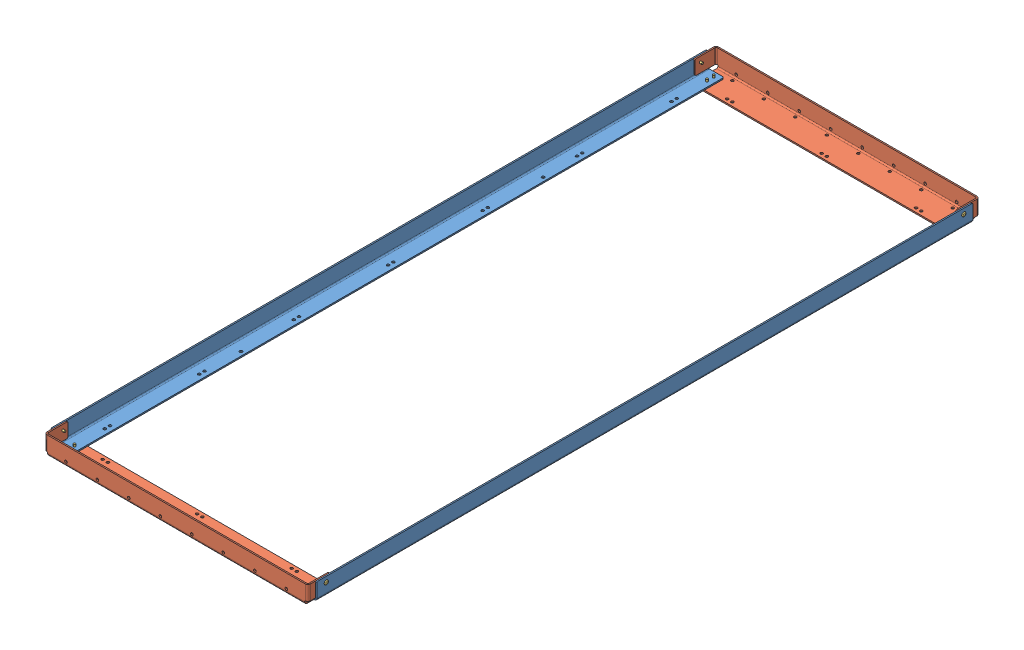
SolidWorks assembly GE-25116, configuration Default. Lengths in mm.
Overall size (647.09 46.05 1625.6).
16 component instances, 3 part files, 33 mates.
Components (placement in the parent):
- GE-25117-1: GE-25117 [Default] at (364.2844 879.7037 1220.4184) size (41.27 41.27 1587.5)
- GE-25117-2: GE-25117 [Default] at (925.6244 879.7037 1220.4184) x (-1 0 0) z (0 0 -1) size (41.27 41.27 1587.5)
- GE-25118-1: GE-25118 [Default] at (644.9544 879.7037 474.2934) size (637.54 44.45 66.67)
- GE-25118-2: GE-25118 [Default] at (644.9544 879.7037 1966.5434) x (-1 0 0) z (0 0 -1) size (637.54 44.45 66.67)
- rivet_.1875_.126-.25-1: rivet_.1875_.126-.25 [Default] at (351.5844 876.5287 2002.1034) x (1 0 0) z (0 -1 0) size (10.01 10.01 13.03)
- rivet_.1875_.126-.25-3: rivet_.1875_.126-.25 [Default] at (351.5844 876.5287 1985.5934) x (0.982082 0 -0.188455) z (0 -1 0) size (10.01 10.01 13.03)
- rivet_.1875_.126-.25-5: rivet_.1875_.126-.25 [Default] at (938.3244 876.5287 2002.1034) x (0.918365 0 -0.395734) z (0 -1 0) size (10.01 10.01 13.03)
- rivet_.1875_.126-.25-7: rivet_.1875_.126-.25 [Default] at (938.3244 876.5287 1985.5934) x (0.8 0 -0.6) z (0 -1 0) size (10.01 10.01 13.03)
- rivet_.1875_.126-.25-9: rivet_.1875_.126-.25 [Default] at (966.8994 908.2787 1991.9434) x (0 0.917795 -0.397056) z (1 0 0) size (10.01 10.01 13.03)
- rivet_.1875_.126-.25-11: rivet_.1875_.126-.25 [Default] at (323.0094 908.2787 1991.9434) x (0 0.089543 -0.995983) z (-1 0 0) size (10.01 10.01 13.03)
- rivet_.1875_.126-.25-13: rivet_.1875_.126-.25 [Default] at (351.5844 876.5287 455.2434) x (0.263225 0 -0.964735) z (0 -1 0) size (10.01 10.01 13.03)
- rivet_.1875_.126-.25-15: rivet_.1875_.126-.25 [Default] at (351.5844 876.5287 438.7334) x (0.120178 0 -0.992752) z (0 -1 0) size (10.01 10.01 13.03)
- rivet_.1875_.126-.25-17: rivet_.1875_.126-.25 [Default] at (323.0094 908.2787 448.8934) x (0 0.141223 -0.989978) z (-1 0 0) size (10.01 10.01 13.03)
- rivet_.1875_.126-.25-19: rivet_.1875_.126-.25 [Default] at (938.3244 876.5287 455.2434) x (0 0 -1) z (0 -1 0) size (10.01 10.01 13.03)
- rivet_.1875_.126-.25-21: rivet_.1875_.126-.25 [Default] at (938.3244 876.5287 438.7334) x (0.030377 0 -0.999538) z (0 -1 0) size (10.01 10.01 13.03)
- rivet_.1875_.126-.25-23: rivet_.1875_.126-.25 [Default] at (966.8994 908.2787 448.8934) x (0 -0.208456 -0.978032) z (1 0 0) size (10.01 10.01 13.03)
Mates (geometry in assembly coordinates):
- Coincident1: coincident anti-aligned: plane of fence_shortrail-1 through (326.1844 879.7037 474.2934) normal (-1 0 0); plane of fence_longrail-1 through (326.1844 879.7037 2014.1684) normal (1 0 0)
- Coincident4: coincident anti-aligned: plane of fence_shortrail-1 through (963.7244 879.7037 474.2934) normal (1 0 0); plane of fence_longrail-2 through (963.7244 879.7037 426.6684) normal (-1 0 0)
- Coincident5: coincident anti-aligned: plane of fence_shortrail-2 through (326.1844 879.7037 1966.5434) normal (-1 0 0); plane of fence_longrail-1 through (326.1844 879.7037 2014.1684) normal (1 0 0)
- Coincident6: coincident anti-aligned: plane of fence_longrail-2 through (925.6244 879.7037 426.6684) normal (0 -1 0); plane of fence_shortrail-1 through (956.1044 879.7037 474.2934) normal (0 1 0)
- Coincident8: coincident anti-aligned: plane of fence_longrail-1 through (364.2844 879.7037 2014.1684) normal (0 -1 0); plane of fence_shortrail-2 through (333.8044 879.7037 1966.5434) normal (0 1 0)
- Coincident12: coincident aligned: plane of fence_longrail-1 through (323.0094 920.9787 2014.1684) normal (0 1 0); plane of fence_shortrail-1 through (326.1844 920.9787 461.5934) normal (0 1 0)
- Concentric1: concentric anti-aligned: cylinder of fence_longrail-1 through (326.1844 908.2787 1991.9434) axis (1 0 0) radius 2.4574; cylinder of fence_shortrail-2 through (326.1844 908.2787 1991.9434) axis (-1 0 0) radius 2.4574
- Concentric2: concentric aligned: cylinder of fence_longrail-2 through (963.7244 908.2787 1991.9434) axis (-1 0 0) radius 2.4574; cylinder of fence_shortrail-2 through (326.1844 908.2787 1991.9434) axis (-1 0 0) radius 2.4574
- Concentric3: concentric anti-aligned: cylinder of fence_longrail-2 through (963.7244 908.2787 448.8934) axis (-1 0 0) radius 2.4574; cylinder of fence_shortrail-1 through (963.7244 908.2787 448.8934) axis (1 0 0) radius 2.4574
- Concentric4: concentric anti-aligned: cylinder of GE-25118-2 through (351.5844 879.7037 2002.1034) axis (0 1 0) radius 2.4574; cylinder of rivet_.1875_.126-.25-1 through (351.5844 887.9587 2002.1034) axis (0 -1 0) radius 2.3813
- Coincident13: coincident anti-aligned: plane of GE-25118-2 through (333.8044 876.5287 1966.5434) normal (0 -1 0); plane of rivet_.1875_.126-.25-1 through (351.5844 876.5287 2002.1034) normal (0 1 0)
- Concentric7: concentric anti-aligned: cylinder of GE-25118-2 through (351.5844 879.7037 1985.5934) axis (0 1 0) radius 2.4574; cylinder of rivet_.1875_.126-.25-3 through (351.5844 887.9587 1985.5934) axis (0 -1 0) radius 2.3813
- Coincident14: coincident anti-aligned: plane of GE-25118-2 through (333.8044 876.5287 1966.5434) normal (0 -1 0); plane of rivet_.1875_.126-.25-3 through (351.5844 876.5287 1985.5934) normal (0 1 0)
- Concentric8: concentric anti-aligned: cylinder of GE-25118-2 through (938.3244 879.7037 2002.1034) axis (0 1 0) radius 2.4574; cylinder of rivet_.1875_.126-.25-5 through (938.3244 887.9587 2002.1034) axis (0 -1 0) radius 2.3813
- Coincident15: coincident anti-aligned: plane of GE-25118-2 through (333.8044 876.5287 1966.5434) normal (0 -1 0); plane of rivet_.1875_.126-.25-5 through (938.3244 876.5287 2002.1034) normal (0 1 0)
- Concentric9: concentric anti-aligned: cylinder of GE-25118-2 through (938.3244 879.7037 1985.5934) axis (0 1 0) radius 2.4574; cylinder of rivet_.1875_.126-.25-7 through (938.3244 887.9587 1985.5934) axis (0 -1 0) radius 2.3813
- Coincident16: coincident anti-aligned: plane of GE-25118-2 through (333.8044 876.5287 1966.5434) normal (0 -1 0); plane of rivet_.1875_.126-.25-7 through (938.3244 876.5287 1985.5934) normal (0 1 0)
- Concentric10: concentric anti-aligned: cylinder of GE-25117-2 through (963.7244 908.2787 1991.9434) axis (-1 0 0) radius 2.4574; cylinder of rivet_.1875_.126-.25-9 through (955.4694 908.2787 1991.9434) axis (1 0 0) radius 2.3813
- Coincident17: coincident anti-aligned: plane of GE-25117-2 through (966.8994 879.7037 426.6684) normal (1 0 0); plane of rivet_.1875_.126-.25-9 through (966.8994 908.2787 1991.9434) normal (-1 0 0)
- Concentric11: concentric anti-aligned: cylinder of GE-25117-1 through (326.1844 908.2787 1991.9434) axis (1 0 0) radius 2.4574; cylinder of rivet_.1875_.126-.25-11 through (334.4394 908.2787 1991.9434) axis (-1 0 0) radius 2.3813
- Coincident18: coincident anti-aligned: plane of GE-25117-1 through (323.0094 879.7037 2014.1684) normal (-1 0 0); plane of rivet_.1875_.126-.25-11 through (323.0094 908.2787 1991.9434) normal (1 0 0)
- Concentric12: concentric anti-aligned: cylinder of GE-25118-1 through (351.5844 879.7037 455.2434) axis (0 1 0) radius 2.4574; cylinder of rivet_.1875_.126-.25-13 through (351.5844 887.9587 455.2434) axis (0 -1 0) radius 2.3813
- Coincident19: coincident anti-aligned: plane of GE-25118-1 through (956.1044 876.5287 474.2934) normal (0 -1 0); plane of rivet_.1875_.126-.25-13 through (351.5844 876.5287 455.2434) normal (0 1 0)
- Concentric13: concentric anti-aligned: cylinder of GE-25118-1 through (351.5844 879.7037 438.7334) axis (0 1 0) radius 2.4574; cylinder of rivet_.1875_.126-.25-15 through (351.5844 887.9587 438.7334) axis (0 -1 0) radius 2.3813
- Coincident20: coincident anti-aligned: plane of GE-25118-1 through (956.1044 876.5287 474.2934) normal (0 -1 0); plane of rivet_.1875_.126-.25-15 through (351.5844 876.5287 438.7334) normal (0 1 0)
- Concentric14: concentric anti-aligned: cylinder of GE-25117-1 through (326.1844 908.2787 448.8934) axis (1 0 0) radius 2.4574; cylinder of rivet_.1875_.126-.25-17 through (334.4394 908.2787 448.8934) axis (-1 0 0) radius 2.3813
- Coincident21: coincident anti-aligned: plane of GE-25117-1 through (323.0094 879.7037 2014.1684) normal (-1 0 0); plane of rivet_.1875_.126-.25-17 through (323.0094 908.2787 448.8934) normal (1 0 0)
- Concentric15: concentric anti-aligned: cylinder of GE-25118-1 through (938.3244 879.7037 455.2434) axis (0 1 0) radius 2.4574; cylinder of rivet_.1875_.126-.25-19 through (938.3244 887.9587 455.2434) axis (0 -1 0) radius 2.3813
- Coincident22: coincident anti-aligned: plane of GE-25118-1 through (956.1044 876.5287 474.2934) normal (0 -1 0); plane of rivet_.1875_.126-.25-19 through (938.3244 876.5287 455.2434) normal (0 1 0)
- Concentric16: concentric anti-aligned: cylinder of GE-25118-1 through (938.3244 879.7037 438.7334) axis (0 1 0) radius 2.4574; cylinder of rivet_.1875_.126-.25-21 through (938.3244 887.9587 438.7334) axis (0 -1 0) radius 2.3813
- Coincident23: coincident anti-aligned: plane of GE-25118-1 through (956.1044 876.5287 474.2934) normal (0 -1 0); plane of rivet_.1875_.126-.25-21 through (938.3244 876.5287 438.7334) normal (0 1 0)
- Concentric17: concentric anti-aligned: cylinder of GE-25117-2 through (963.7244 908.2787 448.8934) axis (-1 0 0) radius 2.4574; cylinder of rivet_.1875_.126-.25-23 through (955.4694 908.2787 448.8934) axis (1 0 0) radius 2.3813
- Coincident24: coincident anti-aligned: plane of GE-25117-2 through (966.8994 879.7037 426.6684) normal (1 0 0); plane of rivet_.1875_.126-.25-23 through (966.8994 908.2787 448.8934) normal (-1 0 0)
